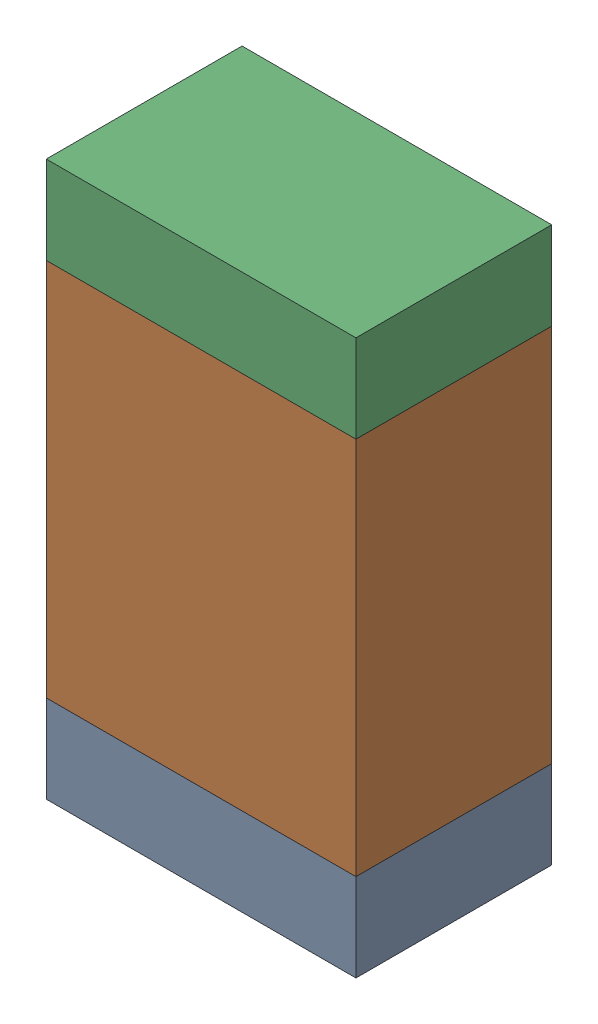
SolidWorks assembly R05-1, configuration Default. Lengths in mm.
Overall size (0.95 1.7 0.6).
6 component instances, 2 part files, 0 mates.
Components (placement in the parent):
- 959206216-1-1: 959206216-1 [Default] at (123.9521 73.9609 0) size (0.95 0.27 0.6)
  - Extruded-31-1: Extruded-31 [Default] at origin size (0.95 0.27 0.6)
- 959206352-1-1: 959206352-1 [Default] at (123.9521 74.6759 0) size (0.95 1.16 0.6)
  - Extruded-32-1: Extruded-32 [Default] at origin size (0.95 1.16 0.6)
- 959206216-1-2: 959206216-1 [Default] at (123.9521 75.3909 0) size (0.95 0.27 0.6)
  - Extruded-31-1: Extruded-31 [Default] at origin size (0.95 0.27 0.6)
